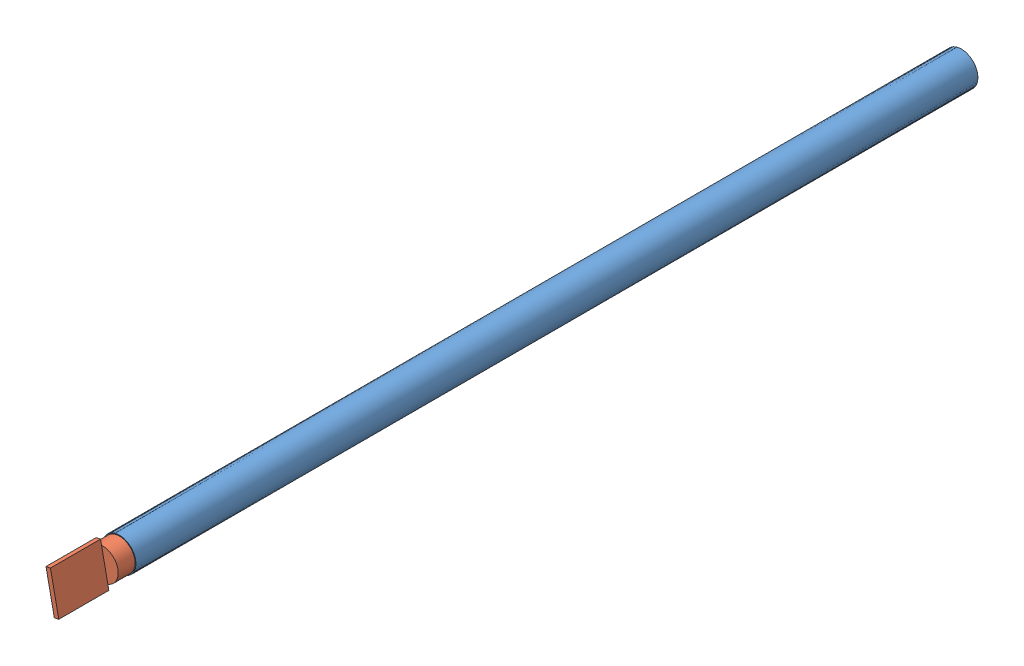
SolidWorks assembly HT_Rohr_ASS, configuration Standard. Lengths in mm.
Overall size (88.49 105.29 2051.2).
2 component instances, 2 part files, 1 mates.
Components (placement in the parent):
- KG Rohr DN 75 - 2000 mm lang-1: KG Rohr DN 75 - 2000 mm lang [Standard] at (-58.7757 16.7655 950) size (75 75 1900)
- Pfropfen-1: Pfropfen [Standard] at (-58.7757 16.7655 2828.2017) x (0.979359 0.202128 0) z (0 0 1) size (71.2 92.82 173)
Mates (geometry in assembly coordinates):
- Konzentrisch1: concentric anti-aligned: circle of KG Rohr DN 75 - 2000 mm lang-1; cylinder of Pfropfen-1 through (-58.7757 16.7655 2888.2017) axis (0 0 -1) radius 35.6
